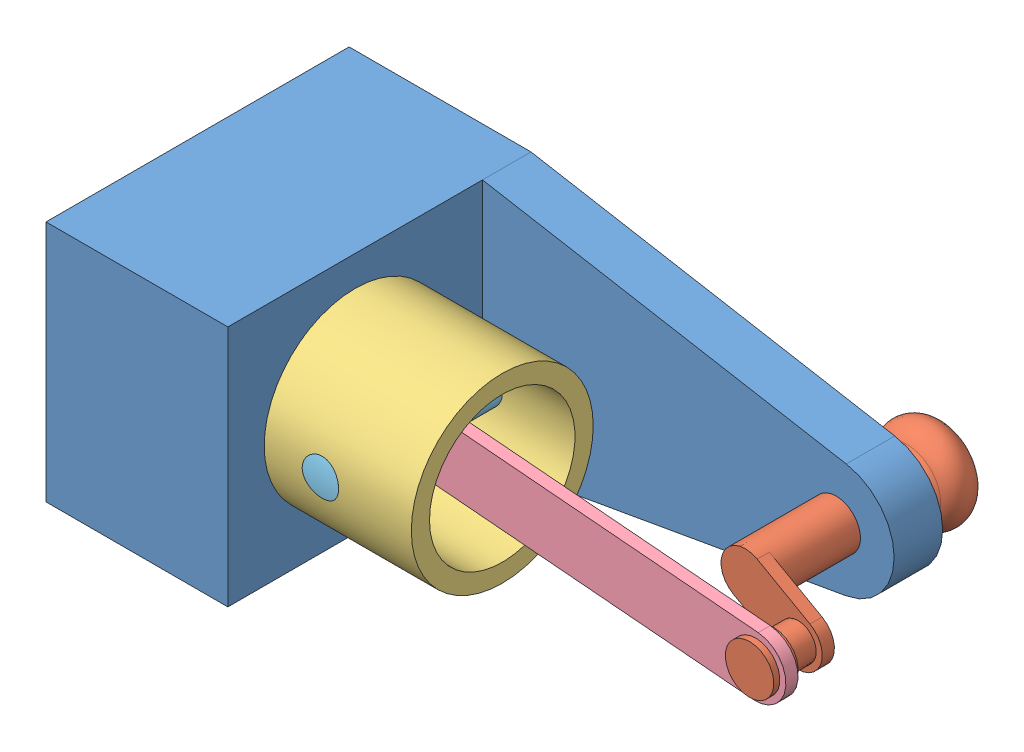
SolidWorks assembly P1, configuration Default. Lengths in mm.
Overall size (260.39 100 150).
5 component instances, 5 part files, 12 mates.
Components (placement in the parent):
- Base-2: Base [Default] x (-1 0 0) z (0 -1 0) size (244.76 125 100)
- Arm-3: Arm [Default] at (21.7794 -12.2743 52.5) x (-0.490974 -0.871174 0) z (0 0 1) size (36.88 53.44 102.5)
- Cylinder-3: Cylinder [Default] at (-160.2002 0 72.5) size (75 75 75)
- Link-3: Link [Default] at (21.7794 -12.2743 72.5) x (-0.996411 0.084651 0) z (0 0 -1) size (170 25 5)
- Pin-3: Pin [Default] at (-122.7002 0 72.5) size (15 15 75)
Mates (geometry in assembly coordinates):
- Coincident1: coincident anti-aligned: plane of Base-2 through (0 0 0) normal (0 0 -1)
- Coincident2: coincident anti-aligned: plane of Base-2 through (0 0 0) normal (0 -1 0)
- Coincident3: coincident anti-aligned: plane of Base-2 through (0 0 0) normal (-1 0 0)
- Concentric14: concentric anti-aligned: cylinder of Cylinder-3 through (-122.7002 0 35) axis (0 0 1) radius 7.5; cylinder of Pin-3 through (-122.7002 0 110) axis (0 0 -1) radius 7.5
- Concentric15: concentric anti-aligned: cylinder of Cylinder-3 through (-85.2002 0 72.5) axis (-1 0 0) radius 37.5; cylinder of Pin-3 through (-130.2002 0 72.5) axis (1 0 0) radius 37.5
- Concentric16: concentric anti-aligned: cylinder of Base-2 through (-220.8473 0 72.5) axis (1 0 0) radius 37.5; cylinder of Cylinder-3 through (-85.2002 0 72.5) axis (-1 0 0) radius 37.5
- Concentric17: concentric aligned: cylinder of Base-2 through (0 0 125) axis (0 0 -1) radius 10; cylinder of Arm-3 through (0 0 57.5) axis (0 0 -1) radius 10
- Distance2: distance = 37.5 mm aligned: plane of Arm-3 through (21.7794 -12.2743 57.5) normal (0 0 1); plane of Base-2 through (0 0 20) normal (0 0 1)
- Concentric18: concentric anti-aligned: cylinder of Arm-3 through (21.7794 -12.2743 77.5) axis (0 0 -1) radius 7.5; cylinder of Link-3 through (21.7794 -12.2743 70) axis (0 0 1) radius 7.5
- Coincident7: coincident anti-aligned: plane of Arm-3 through (21.7794 -12.2743 70) normal (0 0 1); plane of Link-3 through (21.7794 -12.2743 70) normal (0 0 -1)
- Concentric19: concentric anti-aligned: cylinder of Link-3 through (-122.7002 0 70) axis (0 0 1) radius 7.5; cylinder of Pin-3 through (-122.7002 0 110) axis (0 0 -1) radius 7.5
- Coincident8: coincident aligned: unknown of Link-3
